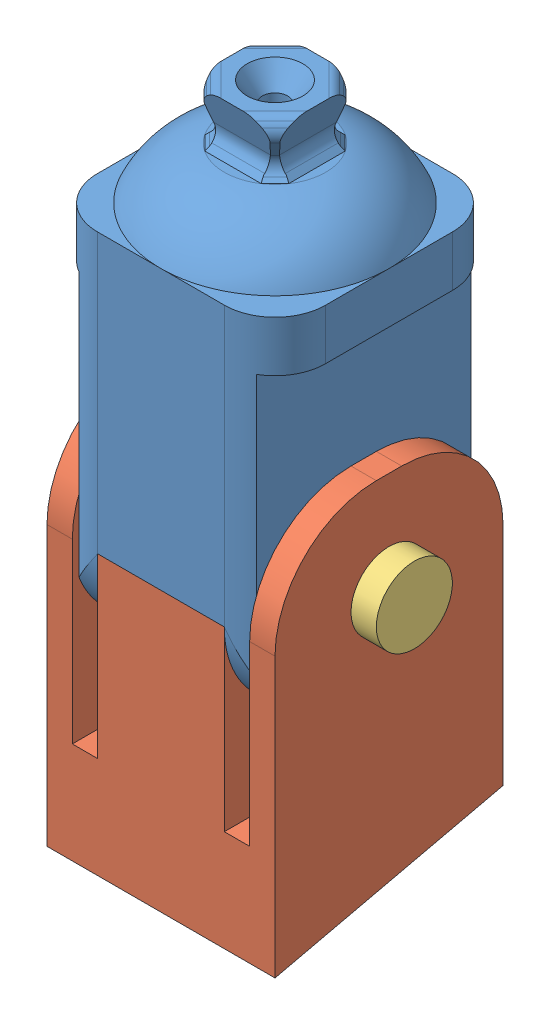
SolidWorks assembly Torsional Spring Assembly, configuration Default. Lengths in mm.
Overall size (55 131 45).
3 component instances, 3 part files, 3 mates.
Components (placement in the parent):
- Torsional Spring Top Half-1: Torsional Spring Top Half [Default] at (32.1369 111.6884 64.9538) size (45 96 45)
- Torsional Spring Bottom Half-1: Torsional Spring Bottom Half [Default] at (32.1369 -13.8116 64.9538) size (45 75 45)
- Torsional Spring Pin-1: Torsional Spring Pin [Default] at (4.6369 41.1884 64.9538) size (55 15 15)
Mates (geometry in assembly coordinates):
- Coincident1: coincident aligned: circle of Torsional Spring Top Half-1; circle of Torsional Spring Bottom Half-1
- Concentric2: concentric aligned: circle of Torsional Spring Bottom Half-1; circle of Torsional Spring Pin-1
- Coincident3: coincident aligned: plane of Torsional Spring Bottom Half-1 through (54.6369 61.1884 87.4538) normal (1 0 0); circle of Torsional Spring Pin-1
